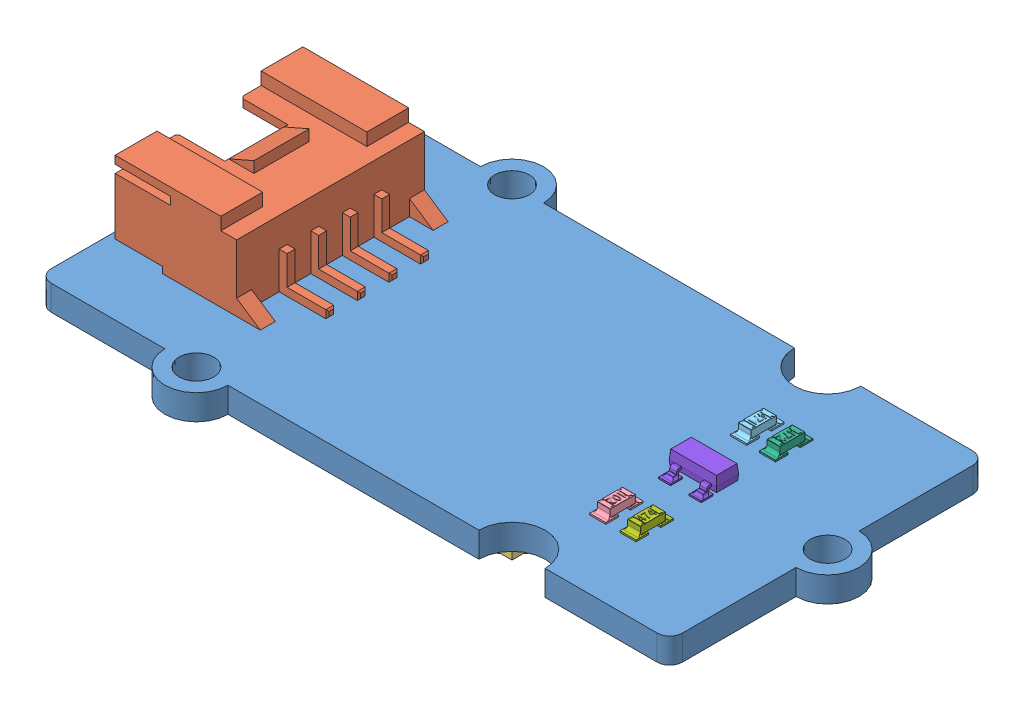
SolidWorks assembly Grove Red LED Button v1.0, configuration Défaut. Lengths in mm.
Overall size (42 12.8 24).
9 component instances, 8 part files, 14 mates.
Components (placement in the parent):
- PCB Grove 20x40 SMD Horizontal - Red LED Button v1.0-1: PCB Grove 20x40 SMD Horizontal - Red LED Button v1.0 [Défaut] at (1.9826 1.6376 0) size (42 6.6 24)
  - PCB Grove 20x40 - Red LED Button-1: PCB Grove 20x40 - Red LED Button [Défaut] at (-8.4131 3.685 42) size (42 1.6 24)
  - Connector Grove SMD Horizontal-1: Connector Grove SMD Horizontal [Défaut] at (-19.9131 9.485 42) x (0 0 -1) z (0 1 0) size (12.95 10.75 5)
- Red Button-1: Red Button [Défaut] at (-6.4306 4.5226 42) x (1 0 0) z (0 -1 0) size (15 12 6.2)
- Resistor 102-1: Resistor 102 [Default] at (4.6655 6.1226 46.481) x (0 0 1) z (-1 0 0) size (2.36 0.62 1.03)
- Resistor 471-1: Resistor 471 [Default] at (4.7992 6.1226 37.681) x (0 0 1) z (-1 0 0) size (2.36 0.62 1.03)
- Resistor 472-1: Resistor 472 [Default] at (6.6192 6.1226 37.681) x (0 0 1) z (-1 0 0) size (2.36 0.62 1.03)
- Resistor 474-1: Resistor 474 [Default] at (6.5855 6.1226 46.481) x (0 0 -1) z (1 0 0) size (2.36 0.62 1.03)
- SSOT3-1: SSOT3 [Default] at (5.6795 6.1226 41.949) size (3 1.13 3.09)
Mates (geometry in assembly coordinates):
- Coïncidente1: coincident anti-aligned: plane of PCB Grove 20x40 SMD Horizontal - Red Led Button v1.0-1/PCB Grove 20x40 - Red Led Button-1 through (-6.4306 4.5226 42) normal (0 -1 0); plane of Red Button-1 through (-6.4306 4.5226 42) normal (0 1 0)
- Coïncidente2: coincident aligned: plane of PCB Grove 20x40 SMD Horizontal - Red Led Button v1.0-1/PCB Grove 20x40 - Red Led Button-1 through (-6.4306 5.3226 42) normal (0 0 1); plane of Red Button-1 through (-6.4306 4.5226 42) normal (0 0 1)
- Coïncidente3: coincident aligned: plane of PCB Grove 20x40 SMD Horizontal - Red Led Button v1.0-1/PCB Grove 20x40 - Red Led Button-1 through (-6.4306 5.3226 42) normal (1 0 0); plane of Red Button-1 through (-6.4306 4.5226 42) normal (1 0 0)
- Coïncidente4: coincident anti-aligned: plane of PCB Grove 20x40 SMD Horizontal - Red Led Button v1.0-1/PCB Grove 20x40 - Red Led Button-1 through (-6.4306 6.1226 42) normal (0 1 0); plane of Resistor 102-1 through (4.6655 6.1226 46.481) normal (0 -1 0)
- Coïncidente5: coincident anti-aligned: plane of PCB Grove 20x40 SMD Horizontal - Red Led Button v1.0-1/PCB Grove 20x40 - Red Led Button-1 through (-6.4306 6.1226 42) normal (0 1 0); plane of Resistor 474-1 through (6.5855 6.1226 46.481) normal (0 -1 0)
- Coïncidente6: coincident anti-aligned: plane of PCB Grove 20x40 SMD Horizontal - Red Led Button v1.0-1/PCB Grove 20x40 - Red Led Button-1 through (-6.4306 6.1226 42) normal (0 1 0); plane of Resistor 471-1 through (4.7992 6.1226 37.681) normal (0 -1 0)
- Coïncidente7: coincident anti-aligned: plane of PCB Grove 20x40 SMD Horizontal - Red Led Button v1.0-1/PCB Grove 20x40 - Red Led Button-1 through (-6.4306 6.1226 42) normal (0 1 0); plane of Resistor 472-1 through (6.6192 6.1226 37.681) normal (0 -1 0)
- Coïncidente9: coincident aligned: plane of Resistor 471-1 through (4.7992 6.1226 37.681) normal (0 0 1); plane of Resistor 472-1 through (6.6192 6.1226 37.681) normal (0 0 1)
- Coïncidente10: coincident anti-aligned: plane of Resistor 102-1 through (4.6655 6.1226 46.481) normal (0 0 1); plane of Resistor 474-1 through (6.5855 6.1226 46.481) normal (0 0 -1)
- Distance1: distance = 4.5 mm aligned: plane of Resistor 471-1 through (4.2892 6.2226 36.5) normal (0 0 -1); plane of PCB Grove 20x40 SMD Horizontal - Red Led Button v1.0-1/PCB Grove 20x40 - Red Led Button-1 through (-6.4306 6.1226 32) normal (0 0 -1)
- Distance2: distance = 0.8 mm anti-aligned: plane of Resistor 471-1 through (5.3092 6.2226 38.062) normal (1 0 0); plane of Resistor 472-1 through (6.1092 6.2226 38.062) normal (-1 0 0)
- Distance3: distance = 13.3 mm aligned: plane of Resistor 102-1 through (4.1555 6.2226 45.3) normal (0 0 -1); plane of PCB Grove 20x40 SMD Horizontal - Red Led Button v1.0-1/PCB Grove 20x40 - Red Led Button-1 through (-6.4306 6.1226 32) normal (0 0 -1)
- Distance4: distance = 0.9 mm anti-aligned: plane of Resistor 102-1 through (5.1755 6.2226 46.862) normal (1 0 0); plane of Resistor 474-1 through (6.0755 6.2226 46.862) normal (-1 0 0)
- Coïncidente15: coincident anti-aligned: plane of PCB Grove 20x40 SMD Horizontal - Red Led Button v1.0-1/PCB Grove 20x40 - Red Led Button-1 through (-6.4306 6.1226 42) normal (0 1 0); plane of SSOT3-1 through (5.6795 6.1226 41.949) normal (0 -1 0)
